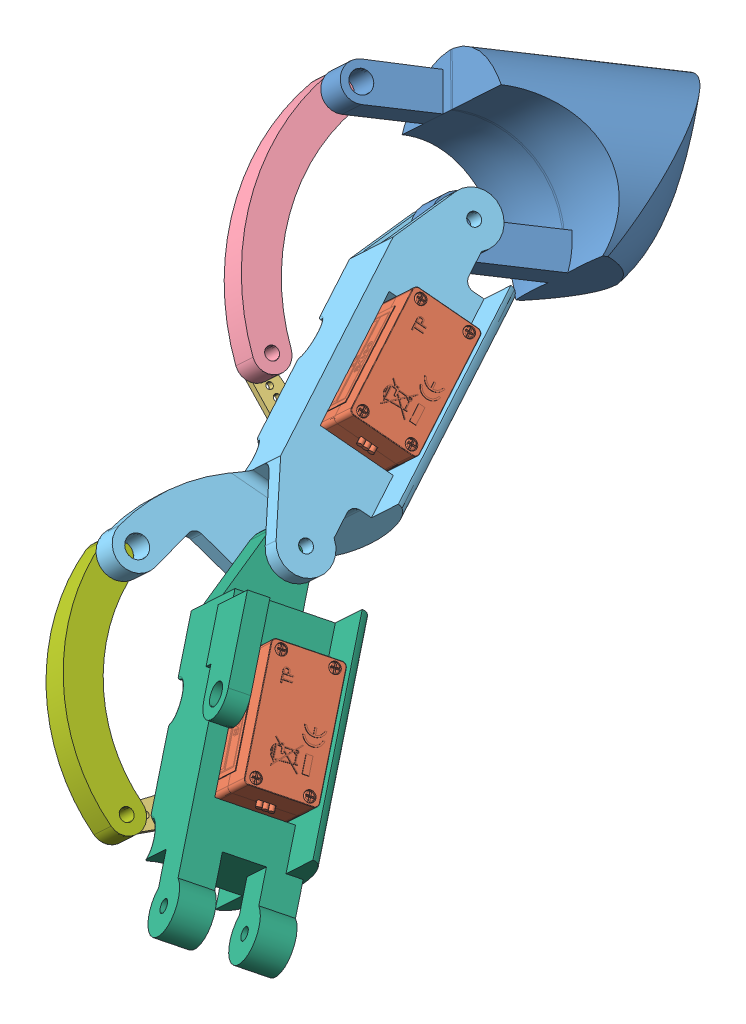
SolidWorks assembly Palm_Thumb_Ass, configuration Default. Lengths in mm.
Overall size (105.29 119.99 154.25).
12 component instances, 7 part files, 8 mates.
Components (placement in the parent):
- Pouce_Ass-1: Pouce_Ass [Défaut] at (159.9767 68.147 -148.4769) x (-0.275729 0.420648 -0.864308) z (-0.633997 0.59627 0.492453) size (114.58 59.46 78.01) (flexible)
  - phalange2_Pouce-1: phalange2_Pouce [Défaut] at (-8.353 -22.7384 161.1487) x (0 -1 0) z (-0.466256 0 0.88465) size (59.46 36.8 53.31)
  - SG90 - Micro Servo Assembly-1: SG90 - Micro Servo Assembly [Default] at (-39.6946 -27.7064 148.9759) size (32.1 31.75 22.59) (flexible)
    - SG90 - Micro Servo 9g - Tower Pro.1-2: SG90 - Micro Servo 9g - Tower Pro.1 [Peça] at origin size (32.1 29.95 12.4)
    - SG90 - Micro Servo 9g - Tower Pro.2-2: SG90 - Micro Servo 9g - Tower Pro.2 [Peça] at (-5.15 21.1 0) x (-0.448 0 -0.894034) z (0.894034 0 -0.448) size (19.5 3.8 6.9)
  - Bras de levier_Pouce-1: Bras de levier_Pouce [Default] at (-11.5118 -8.0064 134.8725) x (0 -1 0) z (-0.704963 0 0.709244) size (5.59 41.05 28.71)
  - SG90 - Servo Socket_Pouce-1: SG90 - Servo Socket_Pouce [Default] at (-58.786 -15.7161 158.6946) x (1 0 0) z (0 1 0) size (76.42 33.67 31.75)
- SG90 - Servo Socket_Pouce2-1: SG90 - Servo Socket_Pouce2 [Default] at (111.6781 116.0676 26.0097) x (-0.438734 0.567792 -0.696508) z (-0.72251 -0.683752 -0.102281) size (67.31 24 32.51)
- SG90 - Micro Servo Assembly-1: SG90 - Micro Servo Assembly [Default] at (117.1606 130.6489 7.0332) x (-0.438734 0.567792 -0.696508) z (-0.534313 0.458361 0.710222) size (32.1 31.75 22.59) (flexible)
  - SG90 - Micro Servo 9g - Tower Pro.1-2: SG90 - Micro Servo 9g - Tower Pro.1 [Peça] at origin size (32.1 29.95 12.4)
  - SG90 - Micro Servo 9g - Tower Pro.2-2: SG90 - Micro Servo 9g - Tower Pro.2 [Peça] at (-5.15 21.1 0) x (0.495386 0 -0.868673) z (0.868673 0 0.495386) size (19.5 3.8 6.9)
- Bras de levier_Pouce2-1: Bras de levier_Pouce2 [Default] at (101.765 120.4914 -8.9163) x (0.72251 0.683752 0.102281) z (-0.004557 -0.143228 0.989679) size (5.59 36.83 29.21)
Mates (geometry in assembly coordinates):
- Concentric1: concentric aligned: circle of Pouce_Ass-1/SG90 - Servo Socket_Pouce-1; circle of SG90 - Servo Socket_Pouce2-1
- Distance1: distance = 0.3969 mm anti-aligned: plane of SG90 - Servo Socket_Pouce2-1 through (119.0991 123.0905 27.0603) normal (0.72251 0.683752 0.102281); plane of Pouce_Ass-1/SG90 - Servo Socket_Pouce-1 through (103.3019 146.3976 -13.2775) normal (-0.72251 -0.683752 -0.102281)
- Concentric2: concentric aligned: circle of SG90 - Servo Socket_Pouce2-1; circle of SG90 - Micro Servo Assembly-1/SG90 - Micro Servo 9g - Tower Pro.1-2
- Parallel1: parallel anti-aligned: plane of SG90 - Servo Socket_Pouce2-1 through (120.3711 128.5834 20.0017) normal (0.534313 -0.458361 -0.710222); plane of SG90 - Micro Servo Assembly-1/SG90 - Micro Servo 9g - Tower Pro.1-2 through (115.0428 119.5837 21.17) normal (-0.534313 0.458361 0.710222)
- Coincident3: coincident anti-aligned: plane of SG90 - Servo Socket_Pouce2-1 through (116.6202 120.7446 26.7093) normal (-0.72251 -0.683752 -0.102281); plane of SG90 - Micro Servo Assembly-1/SG90 - Micro Servo 9g - Tower Pro.1-2 through (117.3033 120.9035 20.822) normal (0.72251 0.683752 0.102281)
- Concentric3: concentric anti-aligned: circle of SG90 - Micro Servo Assembly-1/SG90 - Micro Servo 9g - Tower Pro.2-2; circle of Bras de levier_Pouce2-1
- Concentric4: concentric aligned: circle of Bras de levier_Pouce2-1; circle of Pouce_Ass-1/SG90 - Servo Socket_Pouce-1
- Coincident4: coincident anti-aligned: plane of SG90 - Micro Servo Assembly-1/SG90 - Micro Servo 9g - Tower Pro.2-2 through (105.1866 114.2548 8.6053) normal (0.72251 0.683752 0.102281); plane of Bras de levier_Pouce2-1 through (101.6927 118.2176 6.7949) normal (-0.72251 -0.683752 -0.102281)
